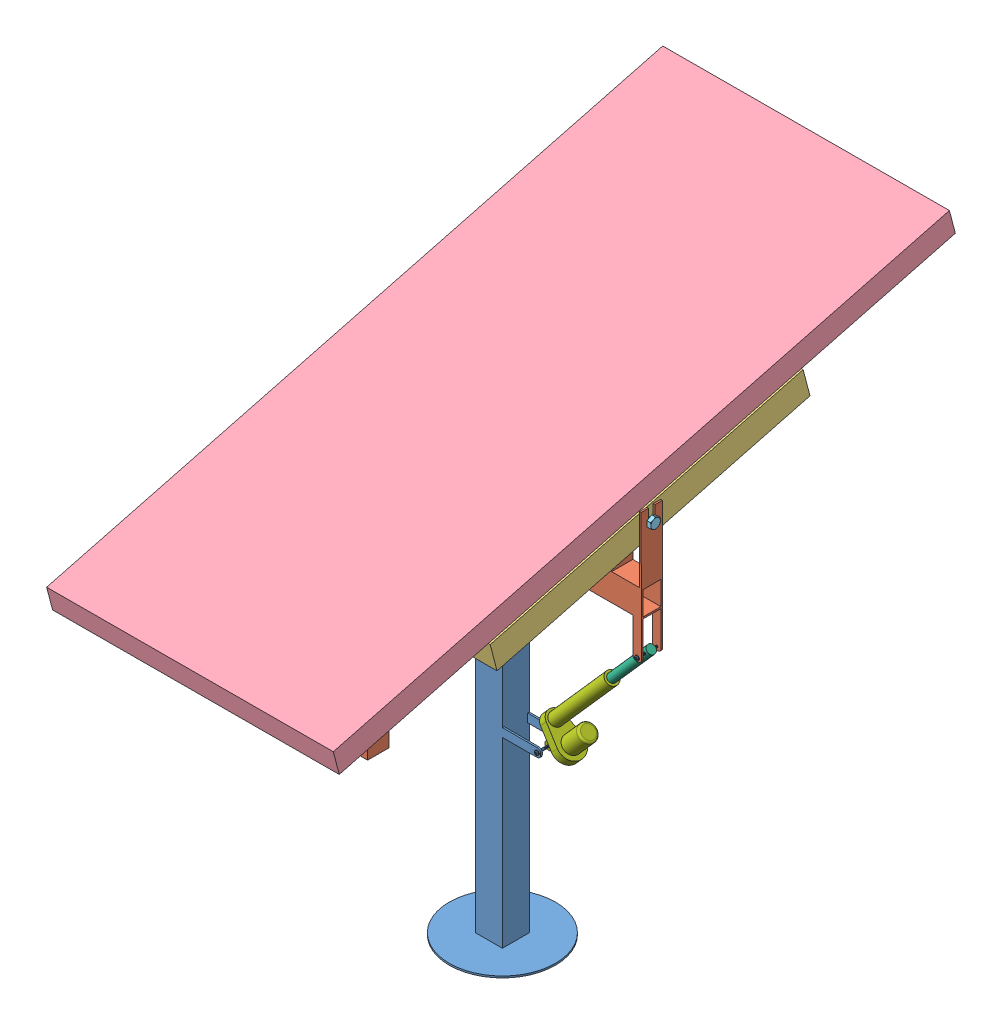
SolidWorks assembly Assembly, configuration Default. Lengths in mm.
Overall size (728.57 1295.85 1465.64).
23 component instances, 10 part files, 46 mates.
Components (placement in the parent):
- Mounting post-1: Mounting post [Default] at (163.3403 117.2732 1026.5976) size (250 904 250)
- Beam-1: Beam [Default] at (518.2429 1014.095 1004.3476) x (0.999995 0.003019 0) z (0 0 1) size (710 825 140)
- Frame-1: Frame [Default] at (158.5243 1168.7395 1037.3311) x (-0.999995 -0.003019 0) z (0.002922 -0.967867 -0.251447) size (700 762 153.5)
- Solar panel-1: Solar panel [Default] at (172.0197 1170.2889 1031.5238) x (-0.000759 0.251446 -0.967871) z (0.999995 0.003019 0) size (1500 55 675)
- heavy hex bolt_ai-1: heavy hex bolt_ai [HHBOLT 0.5000-13x3.25x1-N] at (163.3403 981.2732 985.602) x (0 0 1) z (-1 0 0) size (91.8 25.66 22.23)
- heavy hex bolt_ai-2: heavy hex bolt_ai [HHBOLT 0.5000-13x3.75x1-N] at (-201.3769 1136.9227 1029.3476) x (0.999995 0.003019 0) z (0 0 1) size (104.5 25.66 22.23)
- heavy hex bolt_ai-3: heavy hex bolt_ai [HHBOLT 0.5000-13x3.75x1-N] at (527.111 1139.1223 1029.3476) x (-0.999995 -0.003019 0) z (0 0 1) size (104.5 25.66 22.23)
- heavy hex bolt_ai-4: heavy hex bolt_ai [HHBOLT 0.5000-13x3.75x1-N] at (-154.0954 1042.3196 1231.0031) x (-0.002922 0.967867 0.251447) z (-0.061335 -0.251148 0.966003) size (104.5 25.66 22.23)
- heavy hex bolt_ai-5: heavy hex bolt_ai [HHBOLT 0.5000-13x3.75x1-N] at (482.4017 1044.2415 1231.0031) x (-0.002922 0.967867 0.251447) z (-0.061335 -0.251148 0.966003) size (104.5 25.66 22.23)
- heavy hex bolt_ai-6: heavy hex bolt_ai [HHBOLT 0.5000-13x3.75x1-N] at (-154.4371 1155.4704 795.4612) x (-0.002922 0.967867 0.251447) z (-0.061335 -0.251148 0.966003) size (104.5 25.66 22.23)
- heavy hex bolt_ai-7: heavy hex bolt_ai [HHBOLT 0.5000-13x3.75x1-N] at (482.06 1157.3923 795.4612) x (-0.002922 0.967867 0.251447) z (-0.061335 -0.251148 0.966003) size (104.5 25.66 22.23)
- 200mm rod-1: 200mm rod [Default] at (368.2755 709.7261 1026.5976) x (0.749242 -0.662296 0) z (0 0 1) size (20 220 20)
- Actuator body 200mm-1: Actuator body 200mm [Default] at (275.8065 605.1179 1026.5976) x (0.749242 -0.662296 0) z (0 0 1) size (100 260 60)
- 300mm rod-1: 300mm rod [Default] at (-159.5263 853.8194 804.0365) x (0.001571 -0.520418 -0.85391) z (0.999995 0.003019 0) size (20 320 20)
- Actuator body 300mm-1: Actuator body 300mm [Default] at (-158.8957 644.9865 931.3115) x (0.001571 -0.520418 -0.85391) z (0.999995 0.003019 0) size (100 360 60)
- binding head screw_ai-1: binding head screw_ai [CR-BHMS 0.19-32x1.875x1-N] at (-115.4567 1120.3736 641.6654) x (-0.999995 -0.003019 0) z (0 0 1) size (50.72 10.13 10.13)
- binding head screw_ai-2: binding head screw_ai [CR-BHMS 0.19-32x1.875x1-N] at (-189.2048 1120.151 641.6654) x (0.999995 0.003019 0) z (0 0 1) size (50.72 10.13 10.13)
- binding head screw_ai-3: binding head screw_ai [CR-BHMS 0.19-32x1.875x1-N] at (-193.6401 601.9436 922.3476) x (0.999995 0.003019 0) z (0 0 1) size (50.72 10.13 10.13)
- binding head screw_ai-4: binding head screw_ai [CR-BHMS 0.19-32x1.875x1-N] at (-123.892 602.1542 922.3476) x (-0.999995 -0.003019 0) z (0 0 1) size (50.72 10.13 10.13)
- binding head screw_ai-5: binding head screw_ai [CR-BHMS 0.19-32x1.875x1-N] at (277.0903 561.2732 991.7234) x (0 0 1) z (-1 0 0) size (50.72 10.13 10.13)
- binding head screw_ai-6: binding head screw_ai [CR-BHMS 0.19-32x1.875x1-N] at (277.0903 561.2732 1061.4718) x (0 0 -1) z (1 0 0) size (50.72 10.13 10.13)
- binding head screw_ai-7: binding head screw_ai [CR-BHMS 0.19-32x1.875x1-N] at (508.6822 868.5655 1057.4718) x (0 0 -1) z (1 0 0) size (50.72 10.13 10.13)
- binding head screw_ai-8: binding head screw_ai [CR-BHMS 0.19-32x1.875x1-N] at (508.6822 868.5655 1001.2234) x (0 0 1) z (-1 0 0) size (50.72 10.13 10.13)
Mates (geometry in assembly coordinates):
- Concentric1: concentric aligned: cylinder of Mounting post-1 through (163.3403 981.2732 143.3476) axis (0 0 1) radius 5; cylinder of Beam-1 through (163.3403 981.2732 388.3476) axis (0 0 1) radius 5
- Concentric4: concentric aligned: cylinder of Beam-1 through (513.8654 1139.0824 1029.3476) axis (0.999995 0.003019 0) radius 7.5; cylinder of Frame-1 through (-186.1314 1136.9687 1029.3476) axis (0.999995 0.003019 0) radius 7.5
- Coincident1: coincident anti-aligned: plane of Mounting post-1 through (135.5903 1021.2732 1054.3476) normal (0 0 -1); plane of Beam-1 through (518.2429 1014.095 1054.3476) normal (0 0 1)
- Coincident3: coincident anti-aligned: plane of Beam-1 through (513.8654 1139.0824 1029.3476) normal (-0.999995 -0.003019 0); plane of Frame-1 through (513.669 1204.1535 652.6053) normal (0.999995 0.003019 0)
- Coincident4: coincident aligned: circle of Frame-1; circle of Solar panel-1
- Coincident5: coincident aligned: circle of Frame-1; circle of Solar panel-1
- Concentric5: concentric anti-aligned: cylinder of Mounting post-1 through (163.3403 981.2732 143.3476) axis (0 0 1) radius 5; cylinder of heavy hex bolt_ai-1 through (163.3403 981.2732 985.602) axis (0 0 -1) radius 6.35
- Coincident6: coincident anti-aligned: plane of Mounting post-1 through (131.5903 1021.2732 994.8476) normal (0 0 -1); plane of heavy hex bolt_ai-1 through (163.3403 994.1048 994.8476) normal (0 0 1)
- Concentric61: concentric aligned: cylinder of Beam-1 through (-188.1314 1136.9627 1029.3476) axis (-0.999995 -0.003019 0) radius 7.5; cylinder of heavy hex bolt_ai-2 through (-201.3769 1136.9227 1029.3476) axis (-0.999995 -0.003019 0) radius 6.35
- Coincident71: coincident anti-aligned: plane of Beam-1 through (-191.5622 948.4515 1054.3476) normal (-0.999995 -0.003019 0); plane of heavy hex bolt_ai-2 through (-192.1701 1149.7822 1029.3476) normal (0.999995 0.003019 0)
- Concentric7: concentric aligned: cylinder of Beam-1 through (513.8654 1139.0824 1029.3476) axis (0.999995 0.003019 0) radius 7.5; cylinder of heavy hex bolt_ai-3 through (527.111 1139.1223 1029.3476) axis (0.999995 0.003019 0) radius 6.35
- Coincident8: coincident anti-aligned: plane of Beam-1 through (518.2429 1014.095 1054.3476) normal (0.999995 0.003019 0); plane of heavy hex bolt_ai-3 through (517.9042 1126.2629 1029.3476) normal (-0.999995 -0.003019 0)
- Concentric8: concentric anti-aligned: cylinder of Frame-1 through (-153.8594 964.1602 1210.6977) axis (-0.002922 0.967867 0.251447) radius 5; cylinder of heavy hex bolt_ai-4 through (-154.0954 1042.3196 1231.0031) axis (0.002922 -0.967867 -0.251447) radius 6.35
- Coincident9: coincident anti-aligned: plane of Frame-1 through (158.7098 1107.2799 1021.3642) normal (0.002922 -0.967867 -0.251447); plane of heavy hex bolt_ai-4 through (-166.9298 1051.4298 1232.5568) normal (-0.002922 0.967867 0.251447)
- Concentric9: concentric anti-aligned: cylinder of Frame-1 through (482.6377 966.082 1210.6977) axis (-0.002922 0.967867 0.251447) radius 5; cylinder of heavy hex bolt_ai-5 through (482.4017 1044.2415 1231.0031) axis (0.002922 -0.967867 -0.251447) radius 6.35
- Coincident10: coincident anti-aligned: plane of Frame-1 through (158.7098 1107.2799 1021.3642) normal (0.002922 -0.967867 -0.251447); plane of heavy hex bolt_ai-5 through (469.5672 1053.3517 1232.5568) normal (-0.002922 0.967867 0.251447)
- Concentric10: concentric anti-aligned: cylinder of Frame-1 through (-154.2011 1077.3109 775.1557) axis (-0.002922 0.967867 0.251447) radius 5; cylinder of heavy hex bolt_ai-6 through (-154.4371 1155.4704 795.4612) axis (0.002922 -0.967867 -0.251447) radius 6.35
- Coincident11: coincident anti-aligned: plane of Frame-1 through (158.7098 1107.2799 1021.3642) normal (0.002922 -0.967867 -0.251447); plane of heavy hex bolt_ai-6 through (-167.2715 1164.5805 797.0148) normal (-0.002922 0.967867 0.251447)
- Concentric11: concentric anti-aligned: cylinder of Frame-1 through (482.296 1079.2328 775.1557) axis (-0.002922 0.967867 0.251447) radius 5; cylinder of heavy hex bolt_ai-7 through (482.06 1157.3923 795.4612) axis (0.002922 -0.967867 -0.251447) radius 6.35
- Coincident12: coincident anti-aligned: plane of Frame-1 through (158.7098 1107.2799 1021.3642) normal (0.002922 -0.967867 -0.251447); plane of heavy hex bolt_ai-7 through (469.2256 1166.5024 797.0148) normal (-0.002922 0.967867 0.251447)
- Concentric62: concentric anti-aligned: cylinder of Mounting post-1 through (277.0903 561.2732 1151.5976) axis (0 0 -1) radius 2.5; cylinder of Actuator body 200mm-1 through (277.0903 561.2732 991.5976) axis (0 0 1) radius 2.5
- Width1: width anti-aligned: plane of Mounting post-1 through (163.3403 117.2732 998.8476) normal (0 0 1); plane of Actuator body 200mm-1 through (163.3403 117.2732 1054.3476) normal (0 0 -1); plane of Mounting post-1 through (264.2995 561.9023 1021.5976) normal (0 0 -1); plane of Actuator body 200mm-1 through (264.2995 561.9023 1031.5976) normal (0 0 1)
- Concentric63: concentric anti-aligned: cylinder of 200mm rod-1 through (513.9806 874.5594 1026.5976) axis (-0.662296 -0.749242 0) radius 10; cylinder of Actuator body 200mm-1 through (270.3199 598.9109 1026.5976) axis (0.662296 0.749242 0) radius 10
- Concentric64: concentric anti-aligned: cylinder of Beam-1 through (508.6822 868.5655 1004.3476) axis (0 0 1) radius 2.5; cylinder of 200mm rod-1 through (508.6822 868.5655 1326.5976) axis (0 0 -1) radius 2.5
- Concentric65: concentric aligned: cylinder of Beam-1 through (-190.5159 601.9531 922.3476) axis (0.999995 0.003019 0) radius 2.5; cylinder of Actuator body 300mm-1 through (-193.7659 601.9432 922.3476) axis (0.999995 0.003019 0) radius 2.5
- Width2: width anti-aligned: plane of Beam-1 through (-187.7539 1011.9633 1004.3476) normal (0.999995 0.003019 0); plane of Actuator body 300mm-1 through (-132.2542 1012.1308 1004.3476) normal (-0.999995 -0.003019 0); plane of Beam-1 through (-163.7611 600.4068 935.0501) normal (-0.999995 -0.003019 0); plane of Actuator body 300mm-1 through (-153.7612 600.4369 935.0501) normal (0.999995 0.003019 0)
- Concentric66: concentric anti-aligned: cylinder of 300mm rod-1 through (-160.3514 1127.0694 637.502) axis (0.002578 -0.853906 0.52042) radius 10; cylinder of Actuator body 300mm-1 through (-158.8744 637.9125 935.6228) axis (-0.002578 0.853906 -0.52042) radius 10
- Concentric67: concentric aligned: cylinder of Frame-1 through (-182.0806 1120.1725 641.6654) axis (-0.999995 -0.003019 0) radius 2.5; cylinder of 300mm rod-1 through (139.6679 1121.144 641.6654) axis (-0.999995 -0.003019 0) radius 2.5
- LimitDistance1: limit distance = 119.6187 mm anti-aligned: plane of 200mm rod-1 through (368.2755 709.7261 1026.5976) normal (-0.662296 -0.749242 0); plane of Actuator body 200mm-1 through (289.0525 620.1027 1026.5976) normal (0.662296 0.749242 0)
- LimitDistance2: limit distance = 224.5619 mm anti-aligned: plane of 300mm rod-1 through (-159.5263 853.8194 804.0365) normal (0.002578 -0.853906 0.52042); plane of Actuator body 300mm-1 through (-158.9473 662.0646 920.9031) normal (-0.002578 0.853906 -0.52042)
- Concentric741: concentric anti-aligned: cylinder of Frame-1 through (-118.5809 1120.3642 641.6654) axis (-0.999995 -0.003019 0) radius 2.5; cylinder of binding head screw_ai-1 through (-90.0569 1120.4503 641.6654) axis (0.999995 0.003019 0) radius 2.413
- Coincident771: coincident anti-aligned: plane of Frame-1 through (-118.7245 1167.9023 1037.3311) normal (0.999995 0.003019 0); plane of binding head screw_ai-1 through (-118.5736 1117.9512 641.6654) normal (-0.999995 -0.003019 0)
- Concentric75: concentric aligned: cylinder of Frame-1 through (-182.0806 1120.1725 641.6654) axis (-0.999995 -0.003019 0) radius 2.5; cylinder of binding head screw_ai-2 through (-214.6047 1120.0743 641.6654) axis (-0.999995 -0.003019 0) radius 2.413
- Coincident78: coincident anti-aligned: plane of Frame-1 through (-186.3278 1202.0399 652.6053) normal (-0.999995 -0.003019 0); plane of binding head screw_ai-2 through (-186.0879 1122.5734 641.6654) normal (0.999995 0.003019 0)
- Concentric76: concentric anti-aligned: cylinder of Beam-1 through (-190.5159 601.9531 922.3476) axis (0.999995 0.003019 0) radius 2.5; cylinder of binding head screw_ai-3 through (-219.04 601.8669 922.3476) axis (-0.999995 -0.003019 0) radius 2.413
- Coincident79: coincident anti-aligned: plane of Beam-1 through (-191.5622 948.4515 1054.3476) normal (-0.999995 -0.003019 0); plane of binding head screw_ai-3 through (-190.5232 604.366 922.3476) normal (0.999995 0.003019 0)
- Concentric77: concentric aligned: cylinder of Beam-1 through (-190.5159 601.9531 922.3476) axis (0.999995 0.003019 0) radius 2.5; cylinder of binding head screw_ai-4 through (-98.4922 602.2309 922.3476) axis (0.999995 0.003019 0) radius 2.413
- Coincident80: coincident anti-aligned: plane of Beam-1 through (-128.0625 948.6432 1054.3476) normal (0.999995 0.003019 0); plane of binding head screw_ai-4 through (-127.0089 599.7318 922.3476) normal (-0.999995 -0.003019 0)
- Concentric78: concentric aligned: cylinder of Mounting post-1 through (277.0903 561.2732 1151.5976) axis (0 0 -1) radius 2.5; cylinder of binding head screw_ai-5 through (277.0903 561.2732 966.3234) axis (0 0 -1) radius 2.413
- Coincident81: coincident anti-aligned: plane of Mounting post-1 through (131.5903 1021.2732 994.8476) normal (0 0 -1); plane of binding head screw_ai-5 through (277.0903 563.6862 994.8476) normal (0 0 1)
- Concentric79: concentric anti-aligned: cylinder of Mounting post-1 through (277.0903 561.2732 1151.5976) axis (0 0 -1) radius 2.5; cylinder of binding head screw_ai-6 through (277.0903 561.2732 1086.8718) axis (0 0 1) radius 2.413
- Coincident82: coincident anti-aligned: plane of Mounting post-1 through (131.5903 1021.2732 1058.3476) normal (0 0 1); plane of binding head screw_ai-6 through (277.0903 563.6862 1058.3476) normal (0 0 -1)
- Concentric80: concentric aligned: cylinder of Beam-1 through (508.6822 868.5655 1004.3476) axis (0 0 1) radius 2.5; cylinder of binding head screw_ai-7 through (508.6822 868.5655 1082.8718) axis (0 0 1) radius 2.413
- Coincident83: coincident anti-aligned: plane of Beam-1 through (518.2429 1014.095 1054.3476) normal (0 0 1); plane of binding head screw_ai-7 through (508.6822 870.9785 1054.3476) normal (0 0 -1)
- Concentric81: concentric anti-aligned: cylinder of Beam-1 through (508.6822 868.5655 1004.3476) axis (0 0 1) radius 2.5; cylinder of binding head screw_ai-8 through (508.6822 868.5655 975.8234) axis (0 0 -1) radius 2.413
- Coincident84: coincident anti-aligned: plane of Beam-1 through (518.2429 1014.095 1004.3476) normal (0 0 -1); plane of binding head screw_ai-8 through (508.6822 870.9785 1004.3476) normal (0 0 1)
